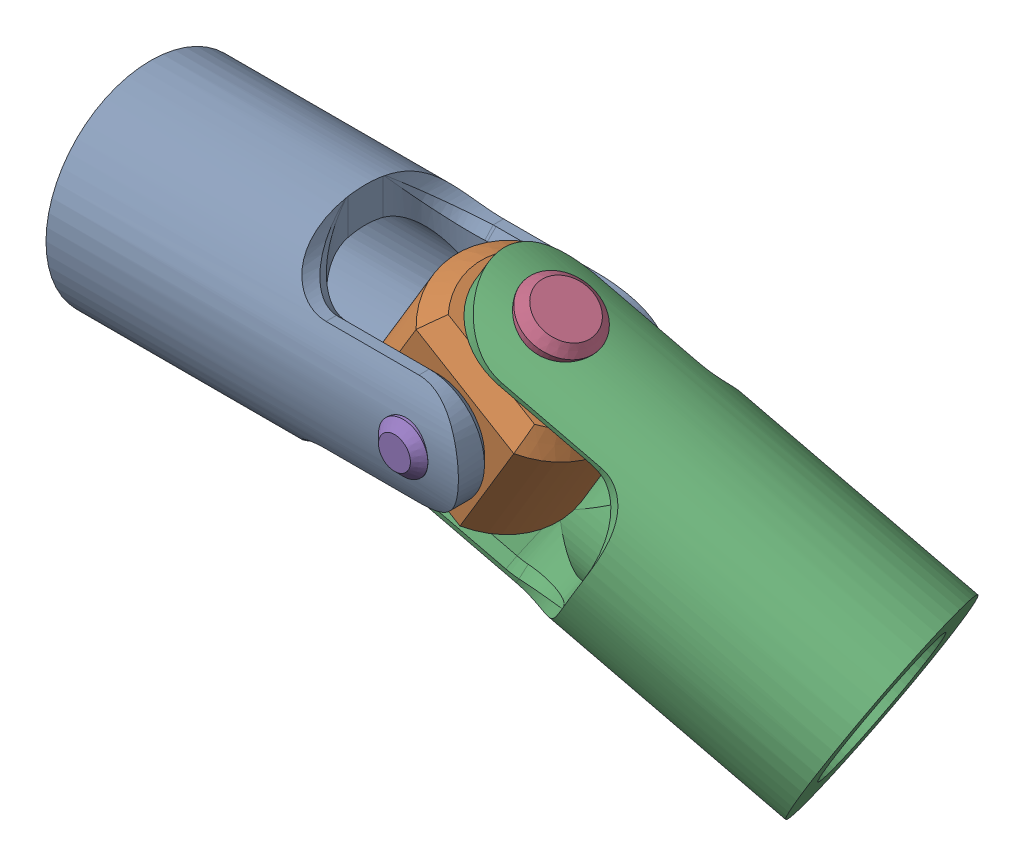
SolidWorks assembly 03_A_CSWA_Lvl9, configuration Default. Lengths in mm.
Overall size (248.81 141.65 104.21).
5 component instances, 5 part files, 10 mates.
Components (placement in the parent):
- Small-Hole-Fork-Base-1: Small-Hole-Fork-Base [Default] at origin size (142 72 72)
- Center-Block-1: Center-Block [Default] at (123 0 0) x (-0.857167 0.515038 0) z (0 0 1) size (62 48 48)
- Large-Hole-Fork-1: Large-Hole-Fork [Default] at (222.8047 -59.9687 -29.0306) x (-0.831706 0.499739 0.241922) z (0.515038 0.857167 0) size (142 72 72)
- Large-Pin-1: Large-Pin [Default] at (123 0 0) x (0.857167 -0.515038 0) z (0 0 1) size (25 78 25)
- Small-Pin-1: Small-Pin [Default] at (123 0 0) size (17 17 78)
Mates (geometry in assembly coordinates):
- Width1: width anti-aligned: plane of Center-Block-1 through (131.8385 -29.7133 24) normal (0 0 1); plane of Small-Hole-Fork-Base-1 through (131.8385 -29.7133 -24) normal (0 0 -1); plane of Center-Block-1 through (142 -36 24) normal (0 0 -1); plane of Small-Hole-Fork-Base-1 through (142 -36 -24) normal (0 0 1)
- Width2: width aligned: plane of Center-Block-1 through (113.7373 -22.1405 0) normal (-0.385945 -0.922522 0); plane of Large-Hole-Fork-1 through (132.2627 22.1405 0) normal (0.385945 0.922522 0); plane of Center-Block-1 through (104.5357 33.7404 -29.6084) normal (-0.385945 -0.922522 0); plane of Large-Hole-Fork-1 through (86.0103 -10.5407 -29.6084) normal (0.385945 0.922522 0)
- Concentric1: concentric aligned: cylinder of Center-Block-1 through (113.7373 -22.1405 0) axis (0.385945 0.922522 0) radius 12.5; cylinder of Large-Hole-Fork-1 through (109.106 -33.2108 0) axis (0.385945 0.922522 0) radius 12.5
- Concentric2: concentric aligned: cylinder of Small-Hole-Fork-Base-1 through (123 0 -36) axis (0 0 1) radius 8.5; cylinder of Center-Block-1 through (123 0 -24) axis (0 0 1) radius 8.5
- Width3: width aligned: plane of Large-Pin-1 through (138.0519 35.9783 0) normal (0.385945 0.922522 0); plane of Center-Block-1 through (107.9481 -35.9783 0) normal (-0.385945 -0.922522 0); plane of Large-Pin-1 through (132.2627 22.1405 0) normal (0.385945 0.922522 0); plane of Center-Block-1 through (113.7373 -22.1405 0) normal (-0.385945 -0.922522 0)
- Concentric3: concentric anti-aligned: cylinder of Center-Block-1 through (113.7373 -22.1405 0) axis (0.385945 0.922522 0) radius 12.5; cylinder of Large-Pin-1 through (138.0519 35.9783 0) axis (-0.385945 -0.922522 0) radius 12.5
- Width4: width aligned: plane of Small-Pin-1 through (123 0 39) normal (0 0 1); plane of Center-Block-1 through (123 0 -39) normal (0 0 -1); plane of Small-Pin-1 through (131.8385 -29.7133 24) normal (0 0 1); plane of Center-Block-1 through (131.8385 -29.7133 -24) normal (0 0 -1)
- Concentric4: concentric anti-aligned: cylinder of Center-Block-1 through (123 0 -24) axis (0 0 1) radius 8.5; cylinder of Small-Pin-1 through (123 0 39) axis (0 0 -1) radius 8.5
- Angle3: planar angle = 0.244346 rad aligned: plane of Center-Block-1 through (127.4579 -30.6778 24) normal (0 0 1); plane of Large-Hole-Fork-1 through (208.8254 -93.5679 -7.6841) normal (0.207368 -0.124599 0.970296)
- Angle4: planar angle = 0.541052 rad aligned: plane of Center-Block-1 through (135.3609 20.572 0) normal (0.515038 0.857167 0); plane of Small-Hole-Fork-Base-1 through (0 19 -36) normal (0 1 0)
